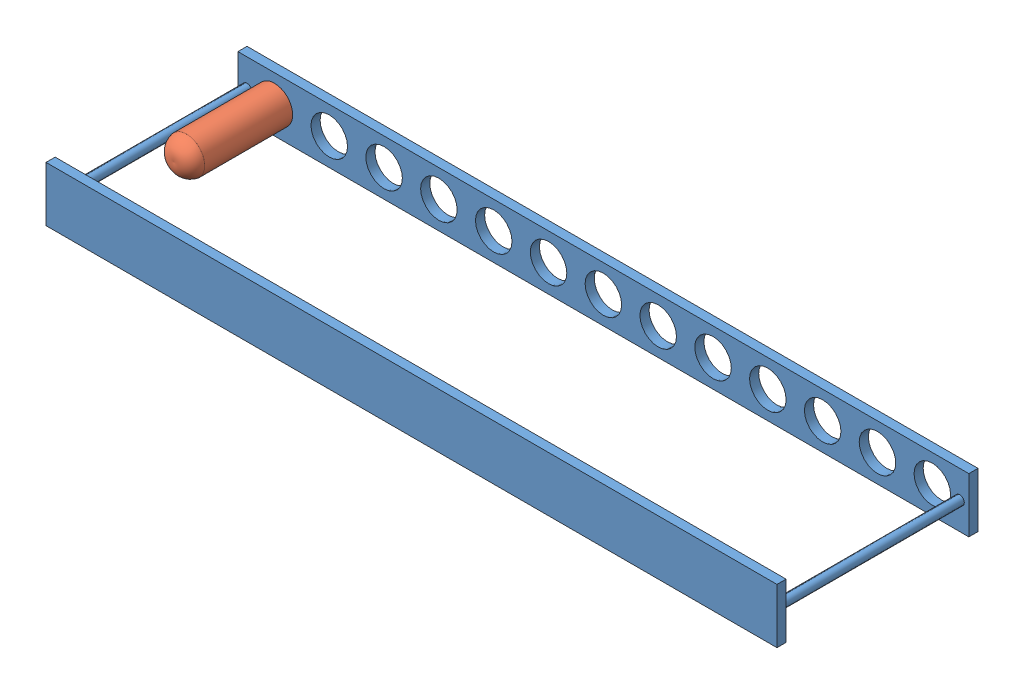
SolidWorks assembly Assem2, configuration Default. Lengths in mm.
Overall size (800 60 221).
2 component instances, 2 part files, 2 mates.
Components (placement in the parent):
- longtubestand-mpang-1: longtubestand-mpang [Default] at (306.7826 415.6758 500.9887) size (800 60 220)
- testtube-mpang-1: testtube-mpang [Default] at (-53.2174 415.6758 620.9887) x (1 0 0) z (0 1 0) size (54.12 121.29 54.12)
Mates (geometry in assembly coordinates):
- Coincident1: coincident: plane of longtubestand-mpang-1 through (306.7826 415.6758 500.9887) normal (0 0 -1); circle of testtube-mpang-1
- Coincident2: coincident aligned: cylinder of longtubestand-mpang-1; cylinder of testtube-mpang-1 through (-53.2174 415.6758 620.9887) axis (0 0 1) radius 20
